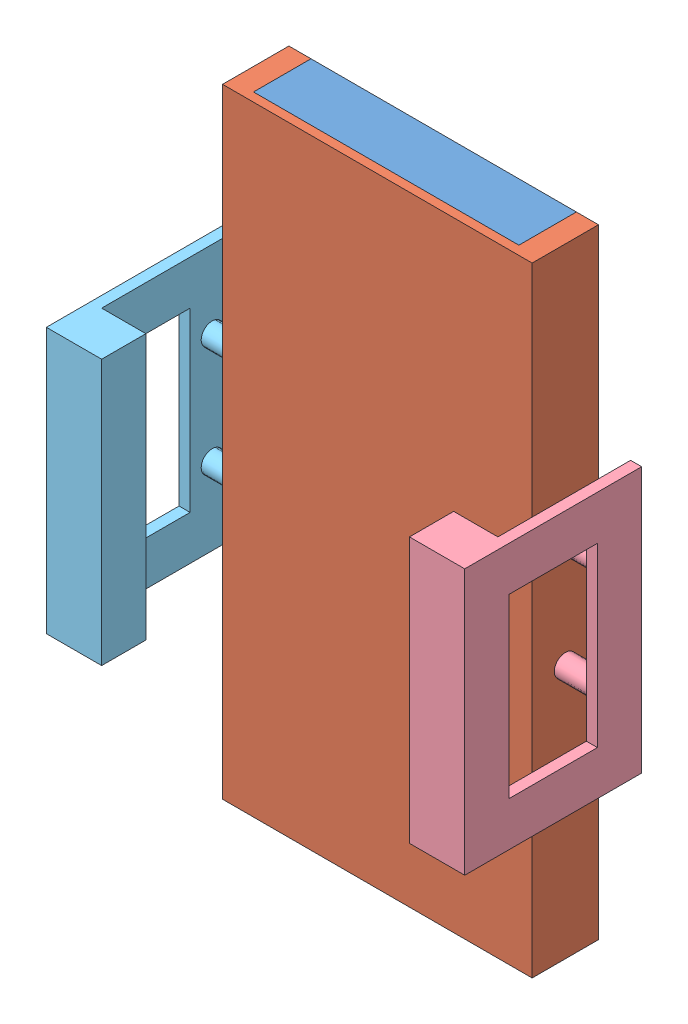
SolidWorks assembly Frame v2, configuration Default. Lengths in mm.
Overall size (94.6 170 65).
5 component instances, 5 part files, 9 mates.
Components (placement in the parent):
- bouchon arriere v2-3: bouchon arriere v2 [Default] at (19.7629 -16.8426 112.3141) size (60 170 31)
- bRAS 2-2: bRAS 2 [Default] at (19.7629 -315.7315 127.3141) size (70 140 15)
- émant collé sur le telephone v2-2: émant collé sur le telephone v2 [Default] at (54.7629 53.1574 114.8141) size (20 20 25.6)
- encadrement bras 2 partie droite-2: encadrement bras 2 partie droite [Default] at (97.0208 63.1574 114.8141) x (1 0 0) z (0 -1 0) size (32.5 40 60)
- encadrement bras 2 partie gauche-2: encadrement bras 2 partie gauche [Default] at (7.4228 63.1574 114.8141) x (1 0 0) z (0 -1 0) size (32.5 40 60)
Mates (geometry in assembly coordinates):
- Concentric36: concentric anti-aligned: cylinder of bouchon arriere v2-3 through (54.7629 53.1574 127.3141) axis (0 0 -1) radius 8.4; cylinder of émant collé sur le telephone v2-2 through (54.7629 53.1574 89.8141) axis (0 0 1) radius 7.4
- Coincident42: coincident anti-aligned: plane of bouchon arriere v2-3 through (19.7629 -16.8426 114.8141) normal (0 0 1); plane of émant collé sur le telephone v2-2 through (54.7629 53.1574 114.8141) normal (0 0 -1)
- Coincident50: coincident anti-aligned: plane of bouchon arriere v2-3 through (19.7629 -16.8426 120.3141) normal (0 0 1); plane of bRAS 2-2 through (19.7629 -315.7315 120.3141) normal (0 0 -1)
- Parallel9: parallel aligned: line of bouchon arriere v2-3 through (24.7629 115.6574 114.8141) axis (0 -1 0); line of bRAS 2-2 through (19.7629 123.1574 112.3141) axis (0 -1 0)
- Coincident58: coincident aligned: line of bouchon arriere v2-3 through (84.7629 123.1574 125.3141) axis (0 0 -1); line of bRAS 2-2 through (84.7629 123.1574 125.3141) axis (0 0 -1)
- Concentric41: concentric anti-aligned: cylinder of bRAS 2-2 through (89.7629 40.6574 119.8141) axis (-1 0 0) radius 2.5; cylinder of encadrement bras 2 partie droite-2 through (69.5208 40.6574 119.8141) axis (1 0 0) radius 2.5
- Concentric42: concentric anti-aligned: cylinder of bRAS 2-2 through (89.7629 65.6574 119.8141) axis (-1 0 0) radius 2.5; cylinder of encadrement bras 2 partie droite-2 through (69.5208 65.6574 119.8141) axis (1 0 0) radius 2.5
- Concentric43: concentric aligned: cylinder of bRAS 2-2 through (89.7629 65.6574 119.8141) axis (-1 0 0) radius 2.5; cylinder of encadrement bras 2 partie gauche-2 through (39.9228 65.6574 119.8141) axis (-1 0 0) radius 2.5
- Concentric44: concentric aligned: cylinder of bRAS 2-2 through (89.7629 40.6574 119.8141) axis (-1 0 0) radius 2.5; cylinder of encadrement bras 2 partie gauche-2 through (39.9228 40.6574 119.8141) axis (-1 0 0) radius 2.5
